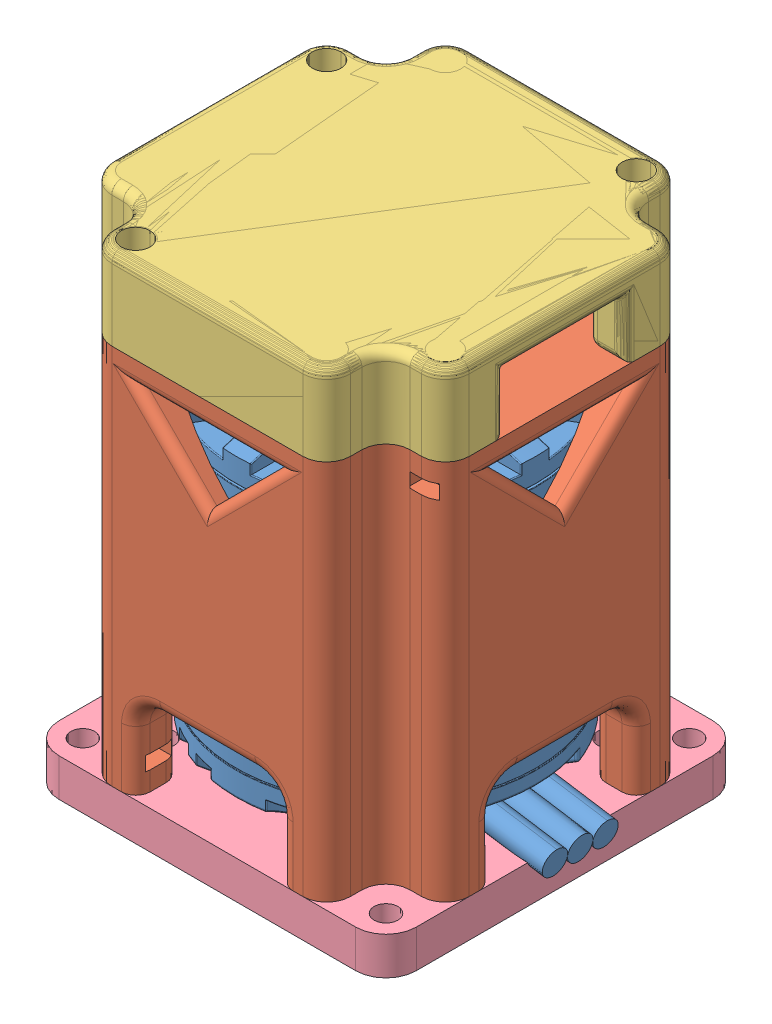
SolidWorks assembly Motor Assembly, configuration Default. Lengths in mm.
Overall size (78.68 127.15 75).
4 component instances, 4 part files, 11 mates.
Components (placement in the parent):
- Motor-1: Motor [Default] at (0 81.9375 0) x (1 0 0) z (0 -1 0) size (72.68 63 120)
- Motor Mount Case-1: Motor Mount Case [Default] at (0 82.9375 0) x (-1 0 0) z (0 0 1) size (75 80 75)
- Motor Mount Encoder Case-1: Motor Mount Encoder Case [Default] at (0 99.9375 0) x (1 0 0) z (0 0 -1) size (75 17.33 75)
- Motor Mount Plate-1: Motor Mount Plate [Default] at (0 1.5875 0) size (75 7.94 75)
Mates (geometry in assembly coordinates):
- Concentric1: concentric anti-aligned: cylinder of Motor-1 through (0 81.9375 0) axis (0 -1 0) radius 31.5; cylinder of Motor Mount Case-1 through (0 7.9365 0) axis (0 1 0) radius 10
- Concentric2: concentric aligned: cylinder of Motor Mount Encoder Case-1 through (0 87.9375 0) axis (0 1 0) radius 33; cylinder of Motor Mount Case-1 through (0 7.9365 0) axis (0 1 0) radius 10
- Coincident1: coincident anti-aligned: plane of Motor Mount Case-1 through (0 87.9375 0) normal (0 1 0); plane of Motor Mount Encoder Case-1 through (0 87.9375 0) normal (0 -1 0)
- Coincident2: coincident anti-aligned: plane of Motor-1 through (0 7.9375 0) normal (0 -1 0); plane of Motor Mount Plate-1 through (0 7.9375 0) normal (0 1 0)
- Concentric4: concentric aligned: cylinder of Motor-1 through (0 81.9375 0) axis (0 -1 0) radius 31.5; cylinder of Motor Mount Plate-1 through (0 7.9375 0) axis (0 -1 0) radius 10
- Coincident3: coincident anti-aligned: plane of Motor Mount Case-1 through (0 7.9375 0) normal (0 -1 0); plane of Motor Mount Plate-1 through (0 7.9375 0) normal (0 1 0)
- Coincident4: coincident aligned: plane of Motor Mount Case-1 through (37.5 7.9375 37.5) normal (0 0 1); plane of Motor Mount Plate-1 through (-37.5 7.9375 37.5) normal (0 0 1)
- Coincident5: coincident anti-aligned: plane of Motor Mount Plate-1 through (0 0 0) normal (0 -1 0)
- Coincident6: coincident aligned: plane of Motor Mount Plate-1 through (0 1.5875 0) normal (1 0 0)
- Coincident7: coincident aligned: plane of Motor Mount Plate-1 through (0 1.5875 0) normal (0 0 1)
- Coincident8: coincident aligned: plane of Motor Mount Case-1 through (37.5 7.9375 -37.5) normal (1 0 0); plane of Motor Mount Encoder Case-1 through (37.5 87.9375 37.5) normal (1 0 0)
